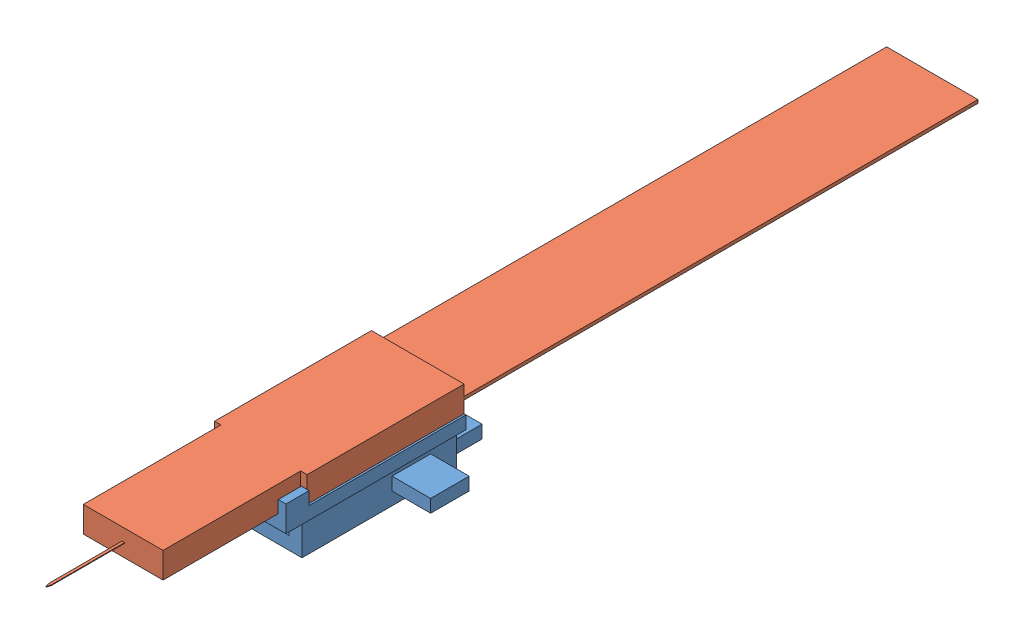
SolidWorks assembly elife im and neuropixel assembly 2019, configuration Default. Lengths in mm.
Overall size (12 6 68.9).
2 component instances, 2 part files, 3 mates.
Components (placement in the parent):
- elife_im-1: elife_im [Default] at origin size (12 5 17.5)
- Neuropixel 2019-1: Neuropixel 2019 [Default] at (0 1 1.1) size (7.2 2 68.9)
Mates (geometry in assembly coordinates):
- Coincident1: coincident anti-aligned: plane of elife_im-1 through (3.75 2 7.2) normal (0 0 -1); plane of Neuropixel 2019-1 through (0.05 3 7.2) normal (0 0 1)
- Distance1: distance = 0.05 mm anti-aligned: plane of elife_im-1 through (3.15 2 7.2) normal (-1 0 0); plane of Neuropixel 2019-1 through (3.1 3 1.1) normal (1 0 0)
- Coincident3: coincident anti-aligned: plane of elife_im-1 through (0 1 0) normal (0 1 0); plane of Neuropixel 2019-1 through (0.05 1 1.1) normal (0 -1 0)
